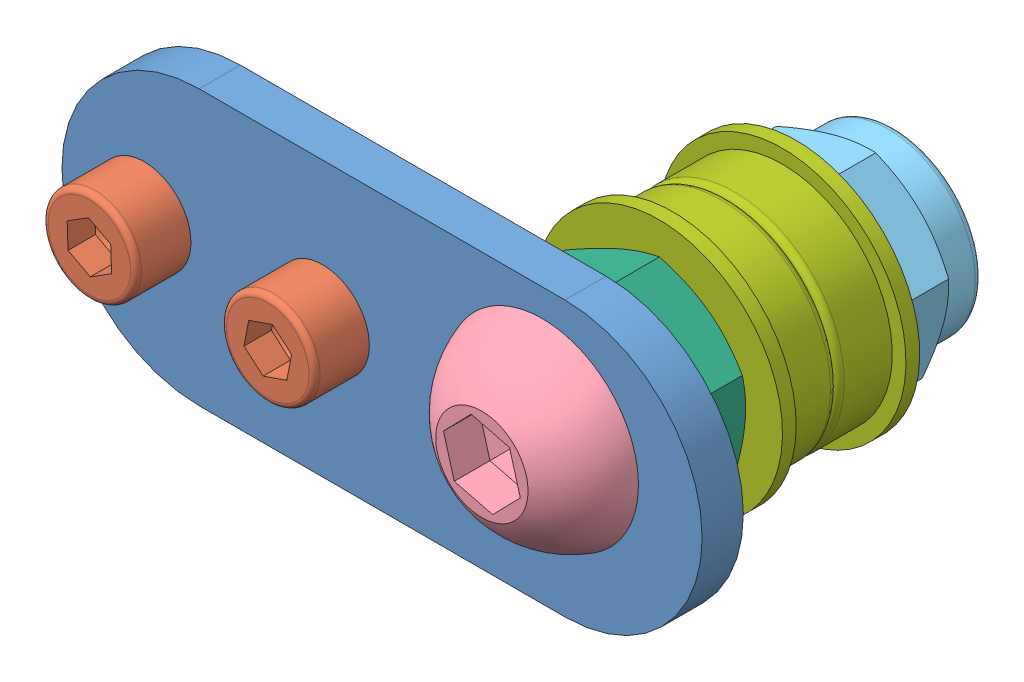
SolidWorks assembly ASM X-Belt Tensioner, configuration Standard. Lengths in mm.
Overall size (52.96 35.92 30.9).
11 component instances, 7 part files, 17 mates.
Components (placement in the parent):
- X Adjustment Block-1: X Adjustment Block [Standard] at (0 0 123.55) x (0 0 1) z (0 1 0) size (3 46.65 20)
- M4X8 Socket Head Screw-1: M4X8 Socket Head Screw [Standard] at (119.0857 138 0) x (0 0 -1) z (0.999363 0.035694 0) size (12 6.8 6.8)
- M5 T-Slot Nut-1: M5 T-Slot Nut [Standard] at (119.0857 138 -5.6373) x (-1 0 0) z (0 0 -1) size (6 9.5 4.1)
- M5 T-Slot Nut-2: M5 T-Slot Nut [Standard] at (132.0857 138 -5.6373) x (-1 0 0) z (0 0 -1) size (6 9.5 4.1)
- M4X8 Socket Head Screw-2: M4X8 Socket Head Screw [Standard] at (132.0857 138 0) x (0 0 -1) z (0.326012 -0.945366 0) size (12 6.8 6.8)
- ASM Roller Bolt-1: ASM Roller Bolt [Standard] at (148.0857 139 4.4) x (0 0 -1) z (0.697352 0.716729 0) size (30.9 25.4 25.4)
  - M8X25 Pan Head Screw-1: M8X25 Pan Head Screw [Standard] at origin size (30.62 14.79 14.79)
  - M8 Self-locking nut-1: M8 Self-locking nut [Standard] at (27.7325 0 0) x (0 0.488663 0.872473) z (1 0 0) size (15.01 13 7.18)
  - M8 nut-1: M8 nut [Standard] at (7.4 0 0) x (0 0.613039 0.790053) z (-1 0 0) size (15.01 13 5.5)
  - F688 pillow-1: F688 pillow [Standard] at (22.9 0 0) x (0 0.424513 0.905422) z (0 -0.905422 0.424513) size (18 5 18)
  - F688 pillow-2: F688 pillow [Standard] at (12.9 0 0) x (0 0.751639 -0.659574) z (0 -0.659574 -0.751639) size (18 5 18)
Mates (geometry in assembly coordinates):
- Konzentrisch29: concentric aligned: cylinder of M4X8 Socket Head Screw-1 through (119.0857 138 0.9416) axis (0 0 1) radius 2; cylinder of M5 T-Slot Nut-1 through (119.0857 138 -8.5663) axis (0 0 1) radius 2.5
- Deckungsgleich27: coincident anti-aligned: plane of M4X8 Socket Head Screw-1 through (118.9644 141.3978 0) normal (0 0 -1); plane of X Adjustment Block-1 through (168.0857 139 0) normal (0 0 1)
- Konzentrisch30: concentric anti-aligned: cylinder of X Adjustment Block-1 through (132.0857 138 -5) axis (0 0 -1) radius 2.1; cylinder of M5 T-Slot Nut-2 through (132.0857 138 -8.5663) axis (0 0 1) radius 2.5
- Konzentrisch31: concentric anti-aligned: cylinder of X Adjustment Block-1 through (119.0857 138 -5) axis (0 0 -1) radius 2.1; cylinder of M5 T-Slot Nut-1 through (119.0857 138 -8.5663) axis (0 0 1) radius 2.5
- Konzentrisch33: concentric anti-aligned: cylinder of X Adjustment Block-1 through (132.0857 138 -5) axis (0 0 -1) radius 2.1; cylinder of M4X8 Socket Head Screw-2 through (132.0857 138 0.9416) axis (0 0 1) radius 2
- Deckungsgleich29: coincident anti-aligned: plane of X Adjustment Block-1 through (168.0857 139 0) normal (0 0 1); plane of M4X8 Socket Head Screw-2 through (135.3 139.1084 0) normal (0 0 -1)
- Konzentrisch71: concentric anti-aligned: cylinder of X Adjustment Block-1 through (148.0857 139 -5) axis (0 0 -1) radius 4.1; cylinder of ASM Roller Bolt-1/M8X25 Pan Head Screw-1 through (148.0857 139 -10) axis (0 0 1) radius 4
- Deckungsgleich64: coincident anti-aligned: plane of X Adjustment Block-1 through (168.0857 139 0) normal (0 0 1); plane of ASM Roller Bolt-1/M8X25 Pan Head Screw-1 through (148.0857 139 0) normal (0 0 -1)
- Deckungsgleich65: coincident anti-aligned: plane of X Adjustment Block-1 through (168.0857 139 -3) normal (0 0 -1); plane of ASM Roller Bolt-1/M8 nut-1 through (161.0046 137.5497 -3) normal (0 0 1)
- Parallel1: parallel aligned: plane of X Adjustment Block-1 through (195.9044 128 0) normal (0 -1 0); plane of M5 T-Slot Nut-2 through (129.0857 133.25 -6.3) normal (0 -1 0)
- Parallel2: parallel aligned: plane of M5 T-Slot Nut-1 through (122.0857 138 -5.6373) normal (1 0 0); plane of M5 T-Slot Nut-2 through (135.0857 138 -5.6373) normal (1 0 0)
- Deckungsgleich66: coincident aligned: plane of M5 T-Slot Nut-1 through (116.0857 133.25 -4.8) normal (0 0 1); plane of M5 T-Slot Nut-2 through (129.0857 133.25 -4.8) normal (0 0 1)
- Abstand1: distance = 1.8 mm anti-aligned: plane of M5 T-Slot Nut-2 through (129.0857 133.25 -4.8) normal (0 0 1); plane of X Adjustment Block-1 through (168.0857 139 -3) normal (0 0 -1)
- Deckungsgleich67: coincident aligned: plane of X Adjustment Block-1 through (168.0857 139 0) normal (0 0 1); plane of assembly through (0 0 0) normal (0 0 1)
- Deckungsgleich68: coincident: plane of X Adjustment Block-1; plane of assembly through (0 0 0) normal (0 0 1)
- Deckungsgleich69: coincident aligned: plane of X Adjustment Block-1 through (0 0 123.55) normal (0 1 0); plane of assembly through (0 0 0) normal (0 1 0)
- Deckungsgleich70: coincident aligned: plane of X Adjustment Block-1; plane of assembly through (0 0 0) normal (1 0 0)
